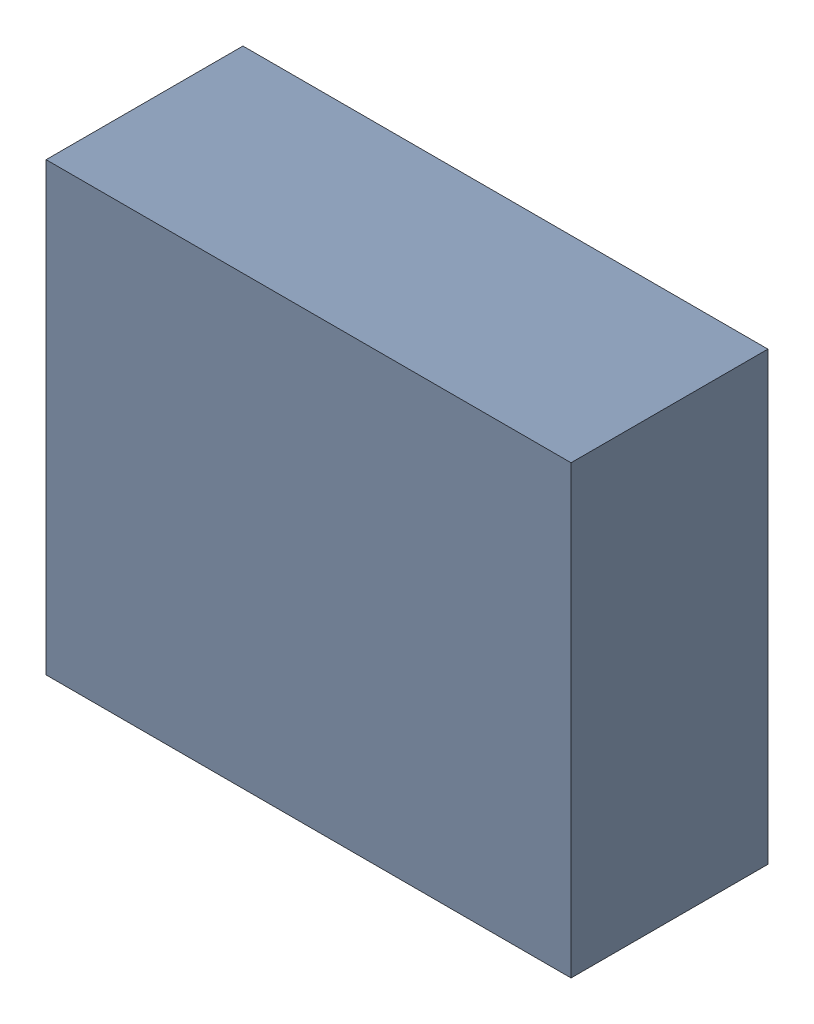
SolidWorks assembly Q11, configuration ﾃﾞﾌｫﾙﾄ. Lengths in mm.
Overall size (2 1.7 0.75).
2 component instances, 1 part files, 0 mates.
Components (placement in the parent):
- 689261376-1: 689261376 [ﾃﾞﾌｫﾙﾄ] at (65 14 0) size (2 1.7 0.75)
  - Extruded_31-1: Extruded_31 [ﾃﾞﾌｫﾙﾄ] at origin size (2 1.7 0.75)
